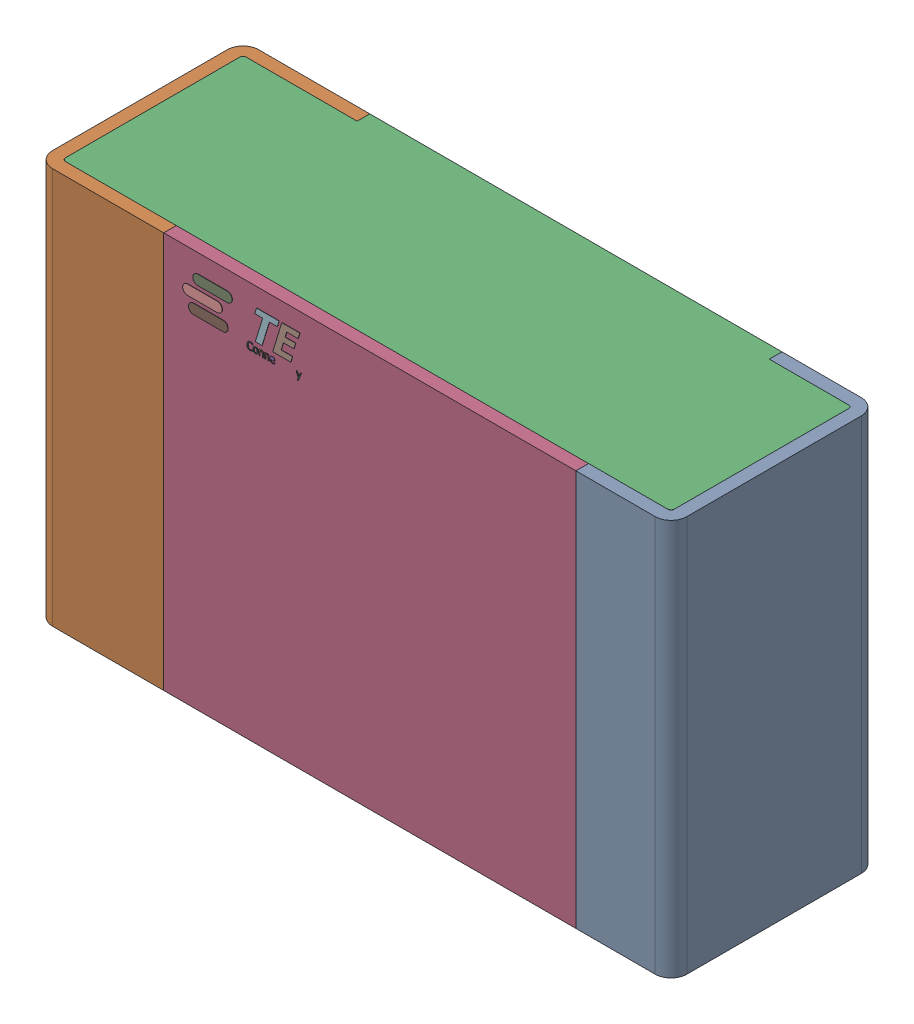
SolidWorks assembly R15.step, configuration Default. Lengths in mm.
Overall size (2 1.25 0.65).
5 component instances, 4 part files, 0 mates.
Components (placement in the parent):
- Res_TE_Connectivity_CPF0805B66R5E1_eec.step-1: Res_TE_Connectivity_CPF0805B66R5E1_eec.step [Default] at (56.841 41.021 0) size (2 1.25 0.65)
  - 1.step-1: 1.step [Default] at origin size (2 1.25 0.65)
  - 2.step-1: 2.step [Default] at origin size (1.92 1.25 0.61)
  - 3.step-1: 3.step [Default] at origin size (1.3 1.25 0.04)
  - TE connectivity Logo 1 (2).step-1: TE connectivity Logo 1 (2).step [Default] at (5.4285 0.313 0.551) x (-1 0 0) z (0 0 1) size (0.37 0.13 0.11)
